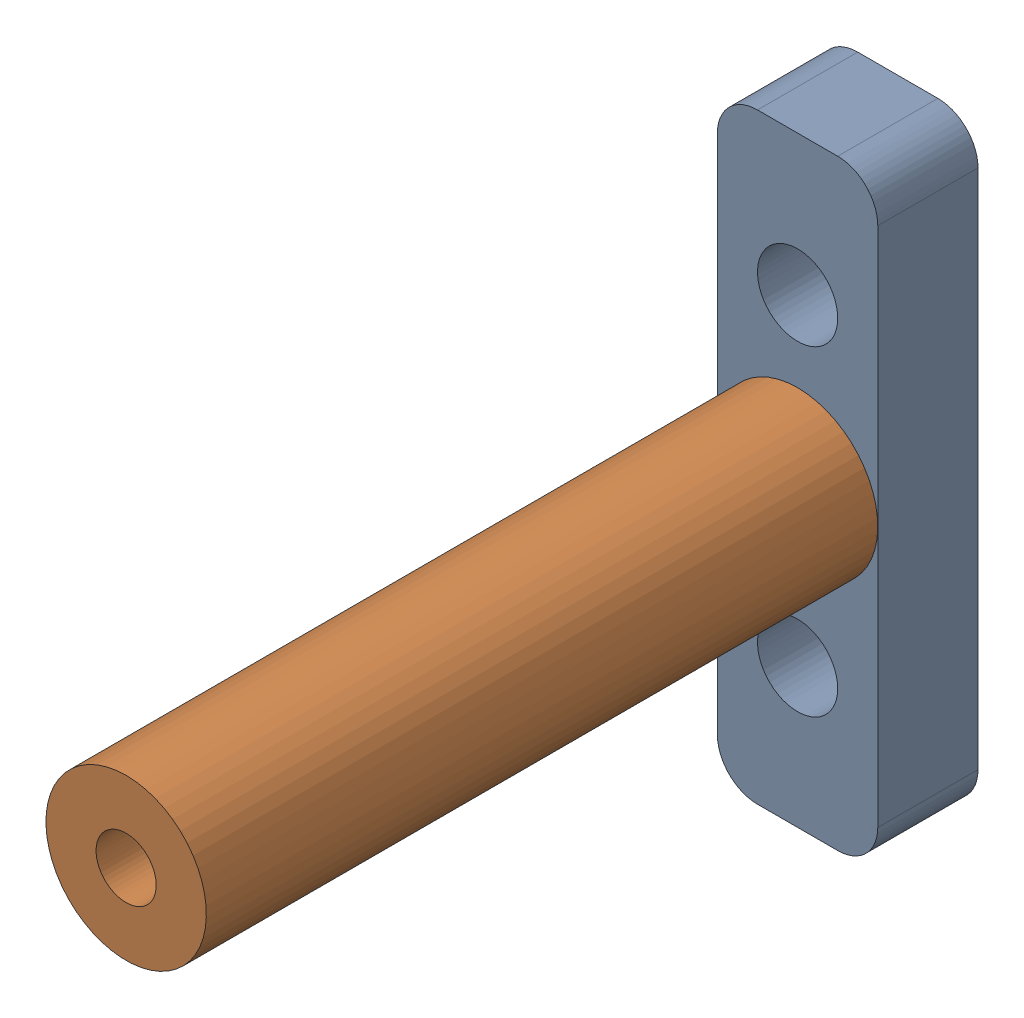
SolidWorks assembly CoperBus3, configuration Default. Lengths in mm.
Overall size (10.73 30 38.5).
2 component instances, 2 part files, 2 mates.
Components (placement in the parent):
- Bus3-1: Bus3 [Default] at origin size (8 30 5)
- Bus1_part-1: Bus1_part [Default] at (4 0 38.5) x (0.895267 0.44553 0) z (0 0 -1) size (8 8 38.5)
Mates (geometry in assembly coordinates):
- Concentric1: concentric anti-aligned: circle of Bus3-1; circle of Bus1_part-1
- Coincident2: coincident anti-aligned: plane of Bus3-1 through (6 13 5) normal (0 0 1); plane of Bus1_part-1 through (4 0 5) normal (0 0 -1)
